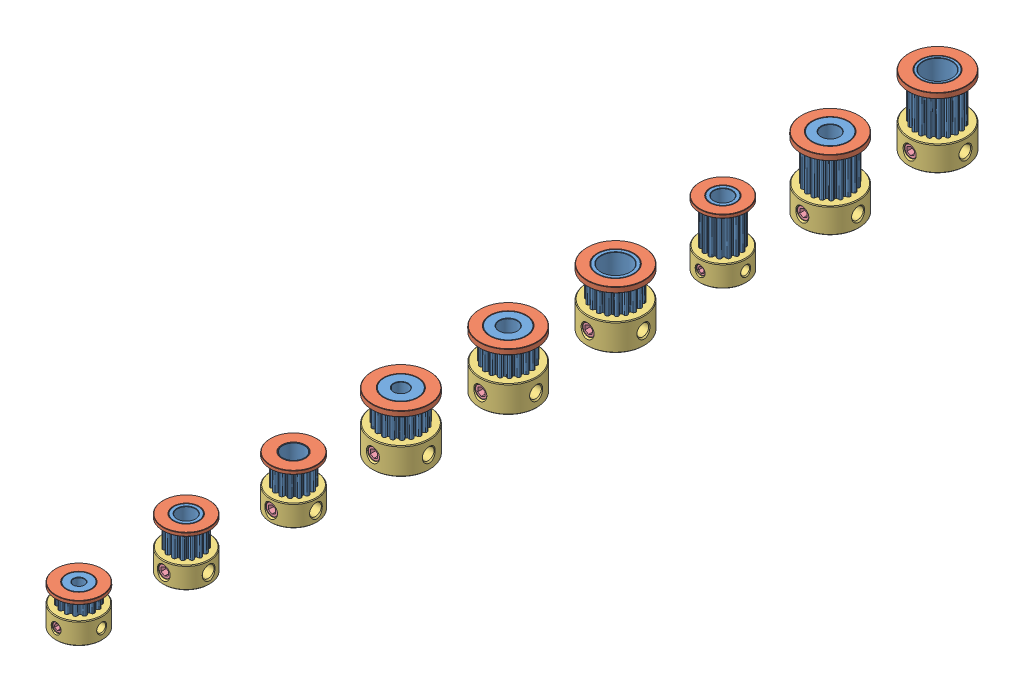
SolidWorks assembly Configurable GT2 Timing Pulleys Lined Up, configuration Default. Lengths in mm.
Overall size (16 19.5 254.5).
45 component instances, 4 part files, 1 mates.
Components (placement in the parent):
- GT2 Timing Pulley, Configurable-1: GT2 Timing Pulley, Configurable [16T W3 B3] at origin size (13 11 13)
  - Body, GT2 Timing Pulley, Configurable-1: Body, GT2 Timing Pulley, Configurable [16T W3 B3] at origin size (9.64 11 9.59)
  - Top Flange, GT2 Timing Pulley, Configurable-1: Top Flange, GT2 Timing Pulley, Configurable [16T W3 B3] at (0 2 0) size (13 1 13)
  - Bottom Base, GT2 Timing Pulley, Configurable-1: Bottom Base, GT2 Timing Pulley, Configurable [16T W3 B3] at (0 -5 0) size (13 6 13)
  - socket set screw flat point_am-2: socket set screw flat point_am [B18.3.6M - M3 x 0.5 x 4 Hex Socket Flat Pt. SS --N] at (0 -5 6) x (0 0 -1) z (-0.040988 -0.99916 0) size (4 3 3)
- GT2 Timing Pulley, Configurable-2: GT2 Timing Pulley, Configurable [16T W6 B5] at (0 0 -30) size (13 14 13)
  - Body, GT2 Timing Pulley, Configurable-1: Body, GT2 Timing Pulley, Configurable [16T W6 B5] at origin size (9.64 14 9.59)
  - Top Flange, GT2 Timing Pulley, Configurable-1: Top Flange, GT2 Timing Pulley, Configurable [16T W6 B5] at (0 3.5 0) size (13 1 13)
  - Bottom Base, GT2 Timing Pulley, Configurable-1: Bottom Base, GT2 Timing Pulley, Configurable [16T W6 B5] at (0 -6.5 0) size (13 6 13)
  - socket set screw flat point_am-2: socket set screw flat point_am [B18.3.6M - M4 x 0.7 x 4 Hex Socket Flat Pt. SS --N] at (0 -6.5 6) x (0 0 -1) z (-0.040988 -0.99916 0) size (4 4 4)
- GT2 Timing Pulley, Configurable-3: GT2 Timing Pulley, Configurable [16T W6 B6] at (0 0 -60) size (13 14 13)
  - Body, GT2 Timing Pulley, Configurable-1: Body, GT2 Timing Pulley, Configurable [16T W6 B6] at origin size (9.64 14 9.59)
  - Top Flange, GT2 Timing Pulley, Configurable-1: Top Flange, GT2 Timing Pulley, Configurable [16T W6 B6] at (0 3.5 0) size (13 1 13)
  - Bottom Base, GT2 Timing Pulley, Configurable-1: Bottom Base, GT2 Timing Pulley, Configurable [16T W6 B6] at (0 -6.5 0) size (13 6 13)
  - socket set screw flat point_am-2: socket set screw flat point_am [B18.3.6M - M4 x 0.7 x 4 Hex Socket Flat Pt. SS --N] at (0 -6.5 6) x (0 0 -1) z (-0.040988 -0.99916 0) size (4 4 4)
- GT2 Timing Pulley, Configurable-4: GT2 Timing Pulley, Configurable [20T W6 B4] at (0 0 -90) size (16 16 16)
  - Body, GT2 Timing Pulley, Configurable-1: Body, GT2 Timing Pulley, Configurable [20T W6 B4] at origin size (12.18 16 12.15)
  - Top Flange, GT2 Timing Pulley, Configurable-1: Top Flange, GT2 Timing Pulley, Configurable [20T W6 B4] at (0 3.5 0) size (16 1.5 16)
  - Bottom Base, GT2 Timing Pulley, Configurable-1: Bottom Base, GT2 Timing Pulley, Configurable [20T W6 B4] at (0 -7.25 0) size (16 7.5 16)
  - socket set screw flat point_am-2: socket set screw flat point_am [B18.3.6M - M4 x 0.7 x 4 Hex Socket Flat Pt. SS --N] at (0 -7.25 7.5) x (0 0 -1) z (-0.040988 -0.99916 0) size (4 4 4)
- GT2 Timing Pulley, Configurable-5: GT2 Timing Pulley, Configurable [20T W6 B5] at (0 0 -120) size (16 16 16)
  - Body, GT2 Timing Pulley, Configurable-1: Body, GT2 Timing Pulley, Configurable [20T W6 B5] at origin size (12.18 16 12.15)
  - Top Flange, GT2 Timing Pulley, Configurable-1: Top Flange, GT2 Timing Pulley, Configurable [20T W6 B5] at (0 3.5 0) size (16 1.5 16)
  - Bottom Base, GT2 Timing Pulley, Configurable-1: Bottom Base, GT2 Timing Pulley, Configurable [20T W6 B5] at (0 -7.25 0) size (16 7.5 16)
  - socket set screw flat point_am-2: socket set screw flat point_am [B18.3.6M - M4 x 0.7 x 4 Hex Socket Flat Pt. SS --N] at (0 -7.25 7.5) x (0 0 -1) z (-0.040988 -0.99916 0) size (4 4 4)
- GT2 Timing Pulley, Configurable-6: GT2 Timing Pulley, Configurable [20T W6 B8] at (0 0 -150) size (16 16 16)
  - Body, GT2 Timing Pulley, Configurable-1: Body, GT2 Timing Pulley, Configurable [20T W6 B8] at origin size (12.18 16 12.15)
  - Top Flange, GT2 Timing Pulley, Configurable-1: Top Flange, GT2 Timing Pulley, Configurable [20T W6 B8] at (0 3.5 0) size (16 1.5 16)
  - Bottom Base, GT2 Timing Pulley, Configurable-1: Bottom Base, GT2 Timing Pulley, Configurable [20T W6 B8] at (0 -7.25 0) size (16 7.5 16)
  - socket set screw flat point_am-2: socket set screw flat point_am [B18.3.6M - M4 x 0.7 x 4 Hex Socket Flat Pt. SS --N] at (0 -7.25 7.5) x (0 0 -1) z (-0.040988 -0.99916 0) size (4 4 4)
- GT2 Timing Pulley, Configurable-7: GT2 Timing Pulley, Configurable [16T W10 B5] at (0 0 -180) size (13 18 13)
  - Body, GT2 Timing Pulley, Configurable-1: Body, GT2 Timing Pulley, Configurable [16T W10 B5] at origin size (9.64 18 9.59)
  - Top Flange, GT2 Timing Pulley, Configurable-1: Top Flange, GT2 Timing Pulley, Configurable [16T W10 B5] at (0 5.5 0) size (13 1 13)
  - Bottom Base, GT2 Timing Pulley, Configurable-1: Bottom Base, GT2 Timing Pulley, Configurable [16T W10 B5] at (0 -8.5 0) size (13 6 13)
  - socket set screw flat point_am-2: socket set screw flat point_am [B18.3.6M - M3 x 0.5 x 4 Hex Socket Flat Pt. SS --N] at (0 -8.5 6) x (0 0 -1) z (-0.040988 -0.99916 0) size (4 3 3)
- GT2 Timing Pulley, Configurable-8: GT2 Timing Pulley, Configurable [20T W10 B5] at (0 0 -210) size (16 19.5 16)
  - Body, GT2 Timing Pulley, Configurable-1: Body, GT2 Timing Pulley, Configurable [20T W10 B5] at origin size (12.18 19.5 12.15)
  - Top Flange, GT2 Timing Pulley, Configurable-1: Top Flange, GT2 Timing Pulley, Configurable [20T W10 B5] at (0 5.5 0) size (16 1.5 16)
  - Bottom Base, GT2 Timing Pulley, Configurable-1: Bottom Base, GT2 Timing Pulley, Configurable [20T W10 B5] at (0 -9 0) size (16 7 16)
  - socket set screw flat point_am-2: socket set screw flat point_am [B18.3.6M - M4 x 0.7 x 4 Hex Socket Flat Pt. SS --N] at (0 -9 7.5) x (0 0 -1) z (-0.040988 -0.99916 0) size (4 4 4)
- GT2 Timing Pulley, Configurable-9: GT2 Timing Pulley, Configurable [20T W10 B8] at (0 0 -240) size (16 19.5 16)
  - Body, GT2 Timing Pulley, Configurable-1: Body, GT2 Timing Pulley, Configurable [20T W10 B8] at origin size (12.18 19.5 12.15)
  - Top Flange, GT2 Timing Pulley, Configurable-1: Top Flange, GT2 Timing Pulley, Configurable [20T W10 B8] at (0 5.5 0) size (16 1.5 16)
  - Bottom Base, GT2 Timing Pulley, Configurable-1: Bottom Base, GT2 Timing Pulley, Configurable [20T W10 B8] at (0 -9 0) size (16 7 16)
  - socket set screw flat point_am-2: socket set screw flat point_am [B18.3.6M - M4 x 0.7 x 4 Hex Socket Flat Pt. SS --N] at (0 -9 7.5) x (0 0 -1) z (-0.040988 -0.99916 0) size (4 4 4)
Mates (geometry in assembly coordinates):
- Coincident1: coordinate: point of GT2 Timing Pulley, Configurable-1/Body, GT2 Timing Pulley, Configurable-1
